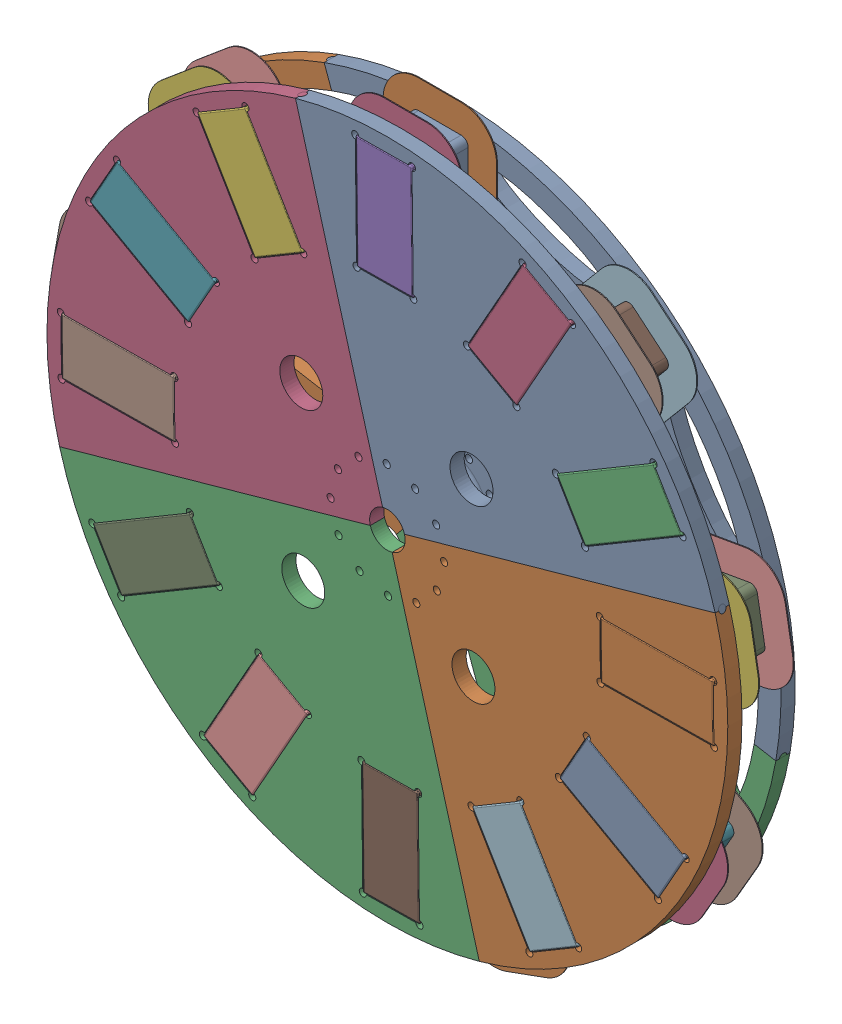
SolidWorks assembly 3DPrintable, configuration Default. Lengths in mm.
Overall size (369 367 30.16).
46 component instances, 6 part files, 14 mates.
Components (placement in the parent):
- CoilSupportX9-1: CoilSupportX9 [Default] at origin size (206.02 178.93 9.53)
- CoilSupportX9-2: CoilSupportX9 [Default] x (-0.5 0.866025 0) z (0 0 1) size (206.02 178.93 9.53)
- CoilSupportX9-3: CoilSupportX9 [Default] x (-0.5 -0.866025 0) z (0 0 1) size (206.02 178.93 9.53)
- IronCore-1: IronCore [Default] at (-9.4615 98.4885 6.35) size (18.92 44.32 15.88)
- IronCore-2: IronCore [Default] at (-70.5551 69.3648 6.35) x (0.766044 0.642788 0) z (0 0 1) size (18.92 44.32 15.88)
- IronCore-3: IronCore [Default] at (-98.6352 7.7846 6.35) x (0.173648 0.984808 0) z (0 0 1) size (18.92 44.32 15.88)
- IronCore-4: IronCore [Default] at (-80.5628 -57.4381 6.35) x (-0.5 0.866025 0) z (0 0 1) size (18.92 44.32 15.88)
- IronCore-5: IronCore [Default] at (-24.7941 -95.7849 6.35) x (-0.939693 0.34202 0) z (0 0 1) size (18.92 44.32 15.88)
- IronCore-6: IronCore [Default] at (42.576 -89.3129 6.35) x (-0.939693 -0.34202 0) z (0 0 1) size (18.92 44.32 15.88)
- IronCore-7: IronCore [Default] at (90.0243 -41.0504 6.35) x (-0.5 -0.866025 0) z (0 0 1) size (18.92 44.32 15.88)
- IronCore-8: IronCore [Default] at (95.3493 26.4201 6.35) x (0.173648 -0.984808 0) z (0 0 1) size (18.92 44.32 15.88)
- IronCore-9: IronCore [Default] at (56.0593 81.5283 6.35) x (0.766044 -0.642788 0) z (0 0 1) size (18.92 44.32 15.88)
- CoilSheath2-1: CoilSheath2 [Default] at (0.0635 0.0635 6.35) size (50.8 76.2 9.53)
- CoilSheath1-1: CoilSheath1 [Default] at (0.0635 0.0635 22.225) x (-1 0 0) z (0 0 -1) size (50.8 76.2 9.53)
- CoilSheath1-2: CoilSheath1 [Default] at (0.0078 0.0895 22.225) x (-0.766044 -0.642788 0) z (0 0 -1) size (50.8 76.2 9.53)
- CoilSheath1-3: CoilSheath1 [Default] at (-0.0515 0.0736 22.225) x (-0.173648 -0.984808 0) z (0 0 -1) size (50.8 76.2 9.53)
- CoilSheath1-4: CoilSheath1 [Default] at (-0.0867 0.0232 22.225) x (0.5 -0.866025 0) z (0 0 -1) size (50.8 76.2 9.53)
- CoilSheath1-5: CoilSheath1 [Default] at (-0.0814 -0.038 22.225) x (0.939693 -0.34202 0) z (0 0 -1) size (50.8 76.2 9.53)
- CoilSheath1-6: CoilSheath1 [Default] at (-0.038 -0.0814 22.225) x (0.939693 0.34202 0) z (0 0 -1) size (50.8 76.2 9.53)
- CoilSheath1-7: CoilSheath1 [Default] at (0.0232 -0.0867 22.225) x (0.5 0.866025 0) z (0 0 -1) size (50.8 76.2 9.53)
- CoilSheath1-8: CoilSheath1 [Default] at (0.0736 -0.0515 22.225) x (-0.173648 0.984808 0) z (0 0 -1) size (50.8 76.2 9.53)
- CoilSheath1-9: CoilSheath1 [Default] at (0.0895 0.0078 22.225) x (-0.766044 0.642788 0) z (0 0 -1) size (50.8 76.2 9.53)
- CoilSheath2-2: CoilSheath2 [Default] at (0.0078 0.0895 6.35) x (0.766044 0.642788 0) z (0 0 1) size (50.8 76.2 9.53)
- CoilSheath2-3: CoilSheath2 [Default] at (-0.0515 0.0736 6.35) x (0.173648 0.984808 0) z (0 0 1) size (50.8 76.2 9.53)
- CoilSheath2-4: CoilSheath2 [Default] at (-0.0867 0.0232 6.35) x (-0.5 0.866025 0) z (0 0 1) size (50.8 76.2 9.53)
- CoilSheath2-5: CoilSheath2 [Default] at (-0.0814 -0.038 6.35) x (-0.939693 0.34202 0) z (0 0 1) size (50.8 76.2 9.53)
- CoilSheath2-6: CoilSheath2 [Default] at (-0.038 -0.0814 6.35) x (-0.939693 -0.34202 0) z (0 0 1) size (50.8 76.2 9.53)
- CoilSheath2-7: CoilSheath2 [Default] at (0.0232 -0.0867 6.35) x (-0.5 -0.866025 0) z (0 0 1) size (50.8 76.2 9.53)
- CoilSheath2-8: CoilSheath2 [Default] at (0.0736 -0.0515 6.35) x (0.173648 -0.984808 0) z (0 0 1) size (50.8 76.2 9.53)
- CoilSheath2-9: CoilSheath2 [Default] at (0.0895 0.0078 6.35) x (0.766044 -0.642788 0) z (0 0 1) size (50.8 76.2 9.53)
- MagnetRotor-1: MagnetRotor [Default] at (0 0 23.8125) x (0.999934 0.01153 0) z (0 0 1) size (187.12 150.35 6.35)
- MagnetRotor-2: MagnetRotor [Default] at (0 0 23.8125) x (0.01153 -0.999934 0) z (0 0 1) size (187.12 150.35 6.35)
- MagnetRotor-3: MagnetRotor [Default] at (0 0 23.8125) x (-0.999934 -0.01153 0) z (0 0 1) size (187.12 150.35 6.35)
- MagnetRotor-4: MagnetRotor [Default] at (0 0 23.8125) x (-0.01153 0.999934 0) z (0 0 1) size (187.12 150.35 6.35)
- magnet-1: magnet [Default] at (-1.3911 120.642 23.8125) x (0.999934 0.01153 0) z (0 0 1) size (25.4 50.8 6.35)
- magnet-2: magnet [Default] at (-61.5257 103.7835 23.8125) x (0.860203 0.509952 0) z (0 0 1) size (25.4 50.8 6.35)
- magnet-3: magnet [Default] at (-105.1745 59.1163 23.8125) x (0.489982 0.871733 0) z (0 0 1) size (25.4 50.8 6.35)
- magnet-4: magnet [Default] at (-120.642 -1.3911 23.8125) x (-0.01153 0.999934 0) z (0 0 1) size (25.4 50.8 6.35)
- magnet-5: magnet [Default] at (-103.7835 -61.5257 23.8125) x (-0.509952 0.860203 0) z (0 0 1) size (25.4 50.8 6.35)
- magnet-6: magnet [Default] at (-59.1163 -105.1745 23.8125) x (-0.871733 0.489982 0) z (0 0 1) size (25.4 50.8 6.35)
- magnet-7: magnet [Default] at (1.3911 -120.642 23.8125) x (-0.999934 -0.01153 0) z (0 0 1) size (25.4 50.8 6.35)
- magnet-8: magnet [Default] at (61.5257 -103.7835 23.8125) x (-0.860203 -0.509952 0) z (0 0 1) size (25.4 50.8 6.35)
- magnet-9: magnet [Default] at (105.1745 -59.1163 23.8125) x (-0.489982 -0.871733 0) z (0 0 1) size (25.4 50.8 6.35)
- magnet-10: magnet [Default] at (120.642 1.3911 23.8125) x (0.01153 -0.999934 0) z (0 0 1) size (25.4 50.8 6.35)
- magnet-11: magnet [Default] at (103.7835 61.5257 23.8125) x (0.509952 -0.860203 0) z (0 0 1) size (25.4 50.8 6.35)
- magnet-12: magnet [Default] at (59.1163 105.1745 23.8125) x (0.871733 -0.489982 0) z (0 0 1) size (25.4 50.8 6.35)
Mates (geometry in assembly coordinates):
- Coincident2: coordinate: point of CoilSupportX9-1
- Concentric1: concentric anti-aligned: cylinder of CoilSupportX9-1 through (0 133.35 6.35) axis (0 0 -1) radius 1.5875; cylinder of IronCore-1 through (0 133.35 22.225) axis (0 0 1) radius 1.6
- Concentric2: concentric anti-aligned: cylinder of CoilSupportX9-1 through (0 107.95 6.35) axis (0 0 -1) radius 1.5875; cylinder of IronCore-1 through (0 107.95 22.225) axis (0 0 1) radius 1.6
- Coincident3: coincident anti-aligned: plane of CoilSupportX9-1 through (0 0 6.35) normal (0 0 1); plane of IronCore-1 through (-9.4615 98.4885 6.35) normal (0 0 -1)
- Coincident4: coincident anti-aligned: plane of CoilSupportX9-1 through (0 0 6.35) normal (0 0 1); plane of CoilSheath2-1 through (-9.4615 142.9385 6.35) normal (0 0 -1)
- Coincident5: coincident anti-aligned: plane of IronCore-1 through (-9.4615 98.4885 22.225) normal (0 -1 0); plane of CoilSheath2-1 through (0.0635 98.4885 15.875) normal (0 1 0)
- Coincident6: coincident anti-aligned: plane of IronCore-1 through (-9.4615 98.4885 22.225) normal (-1 0 0); plane of CoilSheath2-1 through (-9.4615 0.0635 15.875) normal (1 0 0)
- Coincident7: coincident aligned: line of CoilSheath2-1 through (9.5885 142.9385 12.7) axis (-1 0 0); line of CoilSheath1-1 through (9.5885 142.9385 12.7) axis (-1 0 0)
- Coincident8: coincident aligned: line of CoilSheath2-1 through (-9.4615 142.9385 12.7) axis (0 -1 0); line of CoilSheath1-1 through (-9.4615 142.9385 12.7) axis (0 -1 0)
- Distance1: distance = 1.5875 mm anti-aligned: plane of MagnetRotor-1 through (0 0 23.8125) normal (0 0 -1); plane of CoilSheath1-1 through (9.5885 142.9385 22.225) normal (0 0 1)
- Concentric3: concentric aligned: cylinder of CoilSupportX9-1 through (0 0 6.35) axis (0 0 -1) radius 6.3268; cylinder of MagnetRotor-1 through (0 0 30.1625) axis (0 0 -1) radius 7.9375
- Coincident10: coincident anti-aligned: plane of MagnetRotor-1 through (-14.3648 144.3065 30.1625) normal (0.999934 0.01153 0); plane of magnet-1 through (-14.3831 145.8939 30.1625) normal (-0.999934 -0.01153 0)
- Coincident11: coincident anti-aligned: plane of MagnetRotor-1 through (-12.7957 145.9122 30.1625) normal (0.01153 -0.999934 0); plane of magnet-1 through (-14.3831 145.8939 30.1625) normal (-0.01153 0.999934 0)
- Coincident12: coincident aligned: plane of MagnetRotor-1 through (0 0 30.1625) normal (0 0 1); plane of magnet-1 through (-1.3911 120.642 30.1625) normal (0 0 1)
